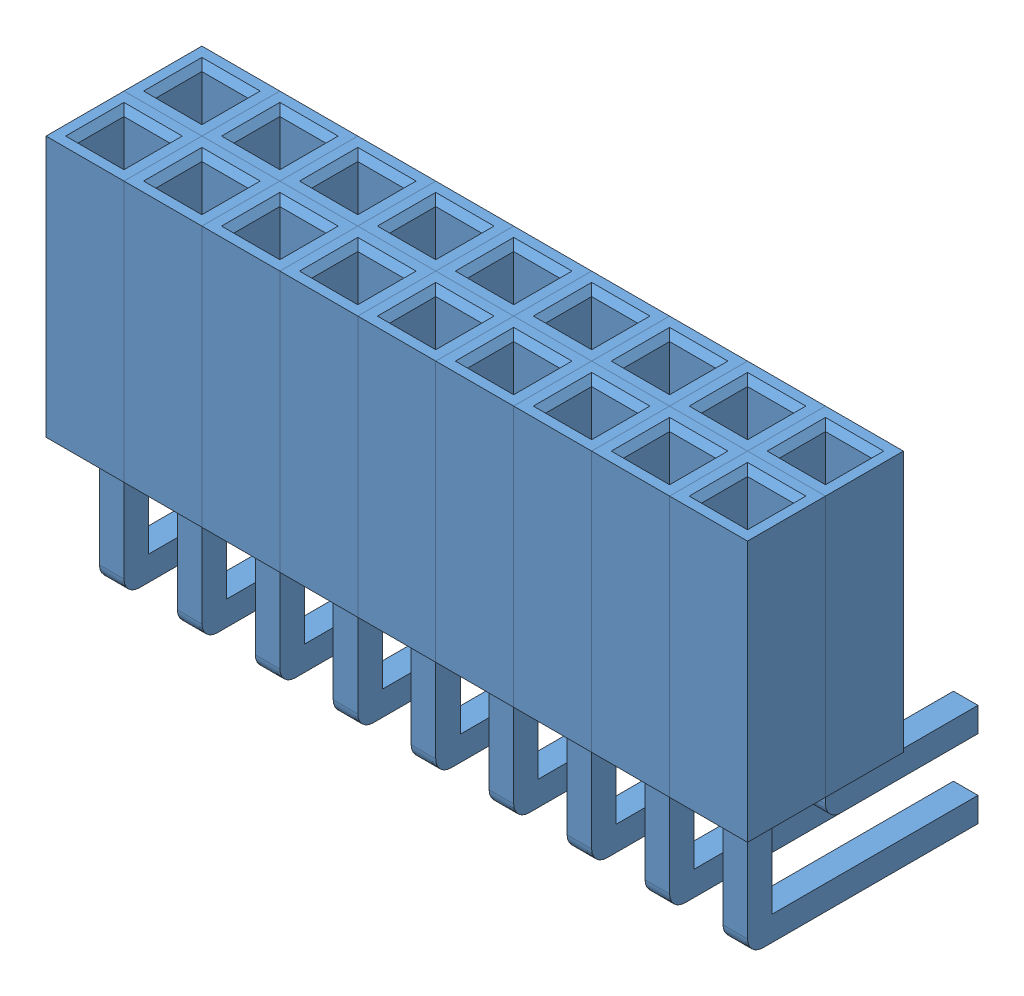
SolidWorks assembly pbd2x9, configuration По умолчанию. Lengths in mm.
Overall size (22.86 12.6 8.58).
21 component instances, 1 part files, 6 mates.
Components (placement in the parent):
- pbd2x3-1: pbd2x3 [По умолчанию] at (0.2433 0.0978 -4.4007) size (7.62 12.6 8.58)
  - pbs1-1: pbs1 [По умолчанию] at (-3.1437 -1.4395 4.583) size (2.54 10.06 6.04)
  - pbs1-2: pbs1 [По умолчанию] at (-0.6037 -1.4395 4.583) size (2.54 10.06 6.04)
  - pbs1-3: pbs1 [По умолчанию] at (1.9363 -1.4395 4.583) size (2.54 10.06 6.04)
  - pbs1-4: pbs1 [dowble] at (-3.1437 -1.4395 7.123) size (2.54 12.6 8.58)
  - pbs1-5: pbs1 [dowble] at (-0.6037 -1.4395 7.123) size (2.54 12.6 8.58)
  - pbs1-6: pbs1 [dowble] at (1.9363 -1.4395 7.123) size (2.54 12.6 8.58)
- pbd2x3-2: pbd2x3 [По умолчанию] at (-7.3767 0.0978 -4.4007) size (7.62 12.6 8.58)
  - pbs1-1: pbs1 [По умолчанию] at (-3.1437 -1.4395 4.583) size (2.54 10.06 6.04)
  - pbs1-2: pbs1 [По умолчанию] at (-0.6037 -1.4395 4.583) size (2.54 10.06 6.04)
  - pbs1-3: pbs1 [По умолчанию] at (1.9363 -1.4395 4.583) size (2.54 10.06 6.04)
  - pbs1-4: pbs1 [dowble] at (-3.1437 -1.4395 7.123) size (2.54 12.6 8.58)
  - pbs1-5: pbs1 [dowble] at (-0.6037 -1.4395 7.123) size (2.54 12.6 8.58)
  - pbs1-6: pbs1 [dowble] at (1.9363 -1.4395 7.123) size (2.54 12.6 8.58)
- pbd2x3-3: pbd2x3 [По умолчанию] at (-14.9967 0.0978 -4.4007) size (7.62 12.6 8.58)
  - pbs1-1: pbs1 [По умолчанию] at (-3.1437 -1.4395 4.583) size (2.54 10.06 6.04)
  - pbs1-2: pbs1 [По умолчанию] at (-0.6037 -1.4395 4.583) size (2.54 10.06 6.04)
  - pbs1-3: pbs1 [По умолчанию] at (1.9363 -1.4395 4.583) size (2.54 10.06 6.04)
  - pbs1-4: pbs1 [dowble] at (-3.1437 -1.4395 7.123) size (2.54 12.6 8.58)
  - pbs1-5: pbs1 [dowble] at (-0.6037 -1.4395 7.123) size (2.54 12.6 8.58)
  - pbs1-6: pbs1 [dowble] at (1.9363 -1.4395 7.123) size (2.54 12.6 8.58)
Mates (geometry in assembly coordinates):
- Совпадение1: coincident aligned: plane of pbd2x3-1/pbs1-1 through (-2.9004 7.1583 -2.3578) normal (0 0 -1); plane of pbd2x3-2/pbs1-3 through (-5.4404 7.1583 -2.3578) normal (0 0 -1)
- Совпадение2: coincident aligned: plane of pbd2x3-1/pbs1-1 through (-2.9004 7.1583 0.1822) normal (0 1 0); plane of pbd2x3-2/pbs1-3 through (-5.4404 7.1583 0.1822) normal (0 1 0)
- Совпадение5: coincident anti-aligned: plane of pbd2x3-1/pbs1-1 through (-2.9004 7.1583 0.1822) normal (-1 0 0); plane of pbd2x3-2/pbs1-3 through (-2.9004 7.1583 0.1822) normal (1 0 0)
- Совпадение6: coincident anti-aligned: plane of pbd2x3-2/pbs1-1 through (-10.5204 7.1583 0.1822) normal (-1 0 0); plane of pbd2x3-3/pbs1-3 through (-10.5204 7.1583 0.1822) normal (1 0 0)
- Совпадение7: coincident aligned: plane of pbd2x3-2/pbs1-1 through (-10.5204 7.1583 -2.3578) normal (0 0 -1); plane of pbd2x3-3/pbs1-3 through (-13.0604 7.1583 -2.3578) normal (0 0 -1)
- Совпадение8: coincident aligned: plane of pbd2x3-2/pbs1-1 through (-10.5204 7.1583 0.1822) normal (0 1 0); plane of pbd2x3-3/pbs1-3 through (-13.0604 7.1583 0.1822) normal (0 1 0)
